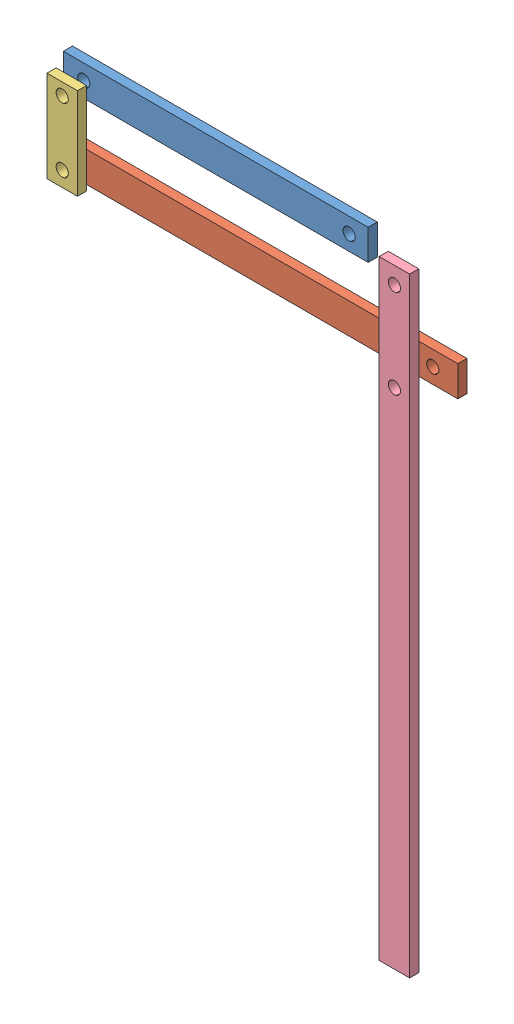
SolidWorks assembly assembly of 4 bar linkage arm, configuration Default. Lengths in mm.
Overall size (131.99 200 10.48).
4 component instances, 4 part files, 0 mates.
Components (placement in the parent):
- arm1-1: arm1 [Default] at (35.3128 56.7564 73.2162) size (100 10 3)
- arm 1 parallel-1: arm 1 parallel [Default] at (52.298 35.2472 75.7637) size (130 10 3)
- arm 2-1: arm 2 [Default] at (-7.576 45.3424 80.6975) size (10 30 3)
- Part4-1: Part4 [Default] at (100.4482 -38.2173 79.7432) size (10 200 3)
